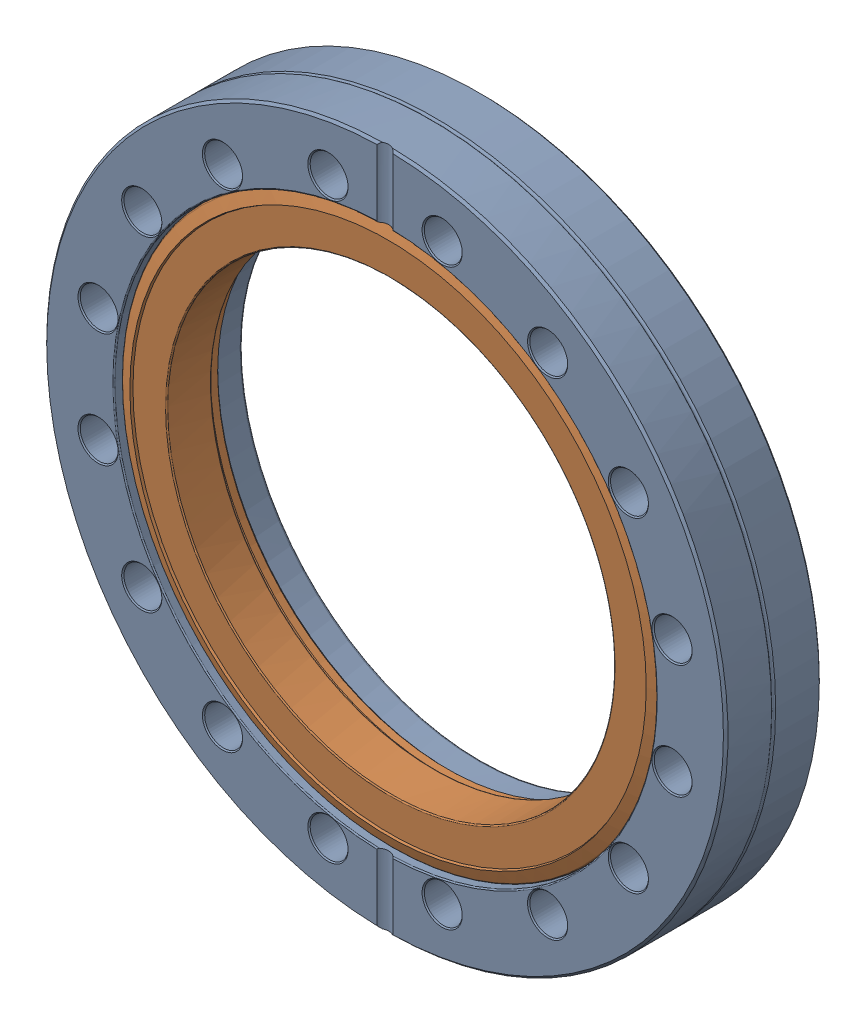
SolidWorks assembly A0000657, configuration Default. Lengths in mm.
Overall size (151.64 151.64 21.38).
2 component instances, 2 part files, 0 mates.
Components (placement in the parent):
- P0000448-1: P0000448 [Default] at (0 0 10.668) x (-1 0 0) z (0 0 -1) size (151.64 151.64 21.38)
- P0000507-1: P0000507 [Default] at (0 0 13.8557) size (120.5 120.5 13.64)
